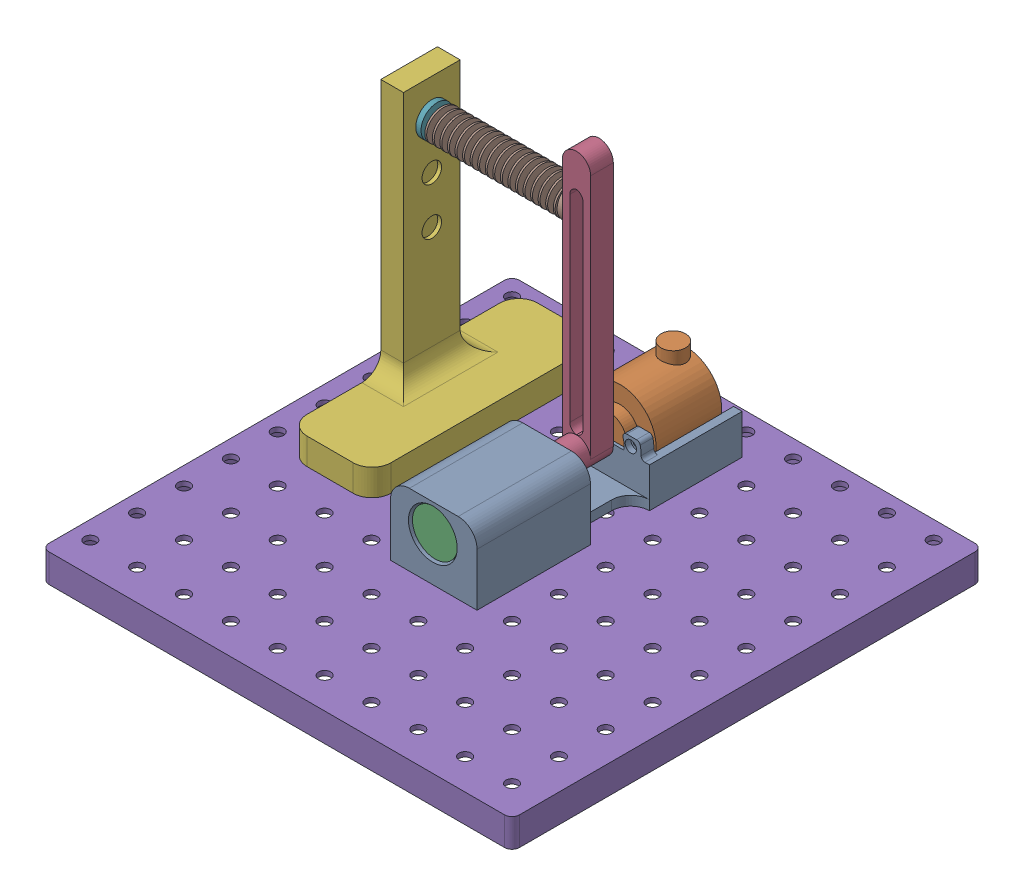
SolidWorks assembly Project 2 Assembly, configuration Default. Lengths in mm.
Overall size (249 175.7 249).
7 component instances, 7 part files, 12 mates.
Components (placement in the parent):
- motor&encoder holder-1: motor&encoder holder [Default] at (-69.5178 38.5336 -52.0637) size (45.82 45 140.35)
- taiss encoder-1: taiss encoder [Default] at (22.6012 51.172 -14.5637) size (38.3 44.15 56)
- motor 2 60RPM-2: motor 2 60RPM [Default] at (22.6012 51.172 62.1913) x (0.999986 -0.005377 0) z (0 0 1) size (25 25 69.8)
- pendulum motor&encoder 041425-1: pendulum motor&encoder 041425 [Default] at (20.7464 78.5914 31.1867) size (15 145 22)
- pegboard-1: pegboard [Default] at (41.1127 27.972 68.4623) x (1 0 0) z (0 0 -1) size (249 15 249)
- pendulum1 body-1: pendulum1 body [Default] at (-84.4985 38.5336 -54.5682) size (44.38 155 122)
- example slinky-1: example slinky [Default] at (12.0053 156.7639 34.3409) x (0 -1 0) z (0 0 -1) size (17 77.8 17)
Mates (geometry in assembly coordinates):
- Concentric1: concentric anti-aligned: cylinder of motor&encoder holder-1 through (22.6012 51.172 -13.5637) axis (0 0 1) radius 19; cylinder of taiss encoder-1 through (22.6012 51.172 20.1863) axis (0 0 -1) radius 19.15
- Concentric2: concentric aligned: cylinder of motor&encoder holder-1 through (22.6012 51.172 26.4363) axis (0 0 -1) radius 10; cylinder of taiss encoder-1 through (22.6012 51.172 26.4363) axis (0 0 -1) radius 10
- Coincident1: coincident anti-aligned: plane of motor&encoder holder-1 through (22.6012 51.172 26.4363) normal (0 0 -1); plane of taiss encoder-1 through (22.6012 51.172 26.4363) normal (0 0 1)
- Concentric6: concentric aligned: circle of motor&encoder holder-1; circle of motor 2 60RPM-2
- Coincident2: coincident anti-aligned: plane of motor&encoder holder-1 through (22.6012 51.172 62.1913) normal (0 0 1); plane of motor 2 60RPM-2 through (22.6012 51.172 62.1913) normal (0 0 -1)
- Concentric8: concentric anti-aligned: cylinder of taiss encoder-1 through (22.6012 51.172 41.4363) axis (0 0 -1) radius 3; cylinder of pendulum motor&encoder 041425-1 through (22.6012 51.172 8.1867) axis (0 0 1) radius 3.1
- Concentric9: concentric aligned: cylinder of motor&encoder holder-1 through (10.696 20.972 15.7863) axis (0 1 0) radius 3.25; cylinder of pegboard-1 through (10.696 15.472 15.7863) axis (0 1 0) radius 3.2
- Concentric10: concentric aligned: cylinder of motor&encoder holder-1 through (35.496 20.972 -9.0137) axis (0 1 0) radius 3.25; cylinder of pegboard-1 through (35.496 15.472 -9.0137) axis (0 1 0) radius 3.2
- Coincident3: coincident anti-aligned: plane of motor&encoder holder-1 through (-69.5178 27.972 -52.0637) normal (0 -1 0); plane of pegboard-1 through (41.1127 27.972 68.4623) normal (0 1 0)
- Concentric13: concentric: cylinder of pegboard-1 through (-63.704 15.472 90.1863) axis (0 1 0) radius 3.2; cylinder of pendulum1 body-1 through (-63.704 20.972 90.1863) axis (0 1 0) radius 3.15
- Concentric14: concentric aligned: cylinder of pegboard-1 through (-63.704 15.472 -9.0137) axis (0 1 0) radius 3.2; cylinder of pendulum1 body-1 through (-63.704 20.972 -9.0137) axis (0 1 0) radius 3.15
- Coincident5: coincident anti-aligned: circle of pendulum1 body-1; circle of example slinky-1
